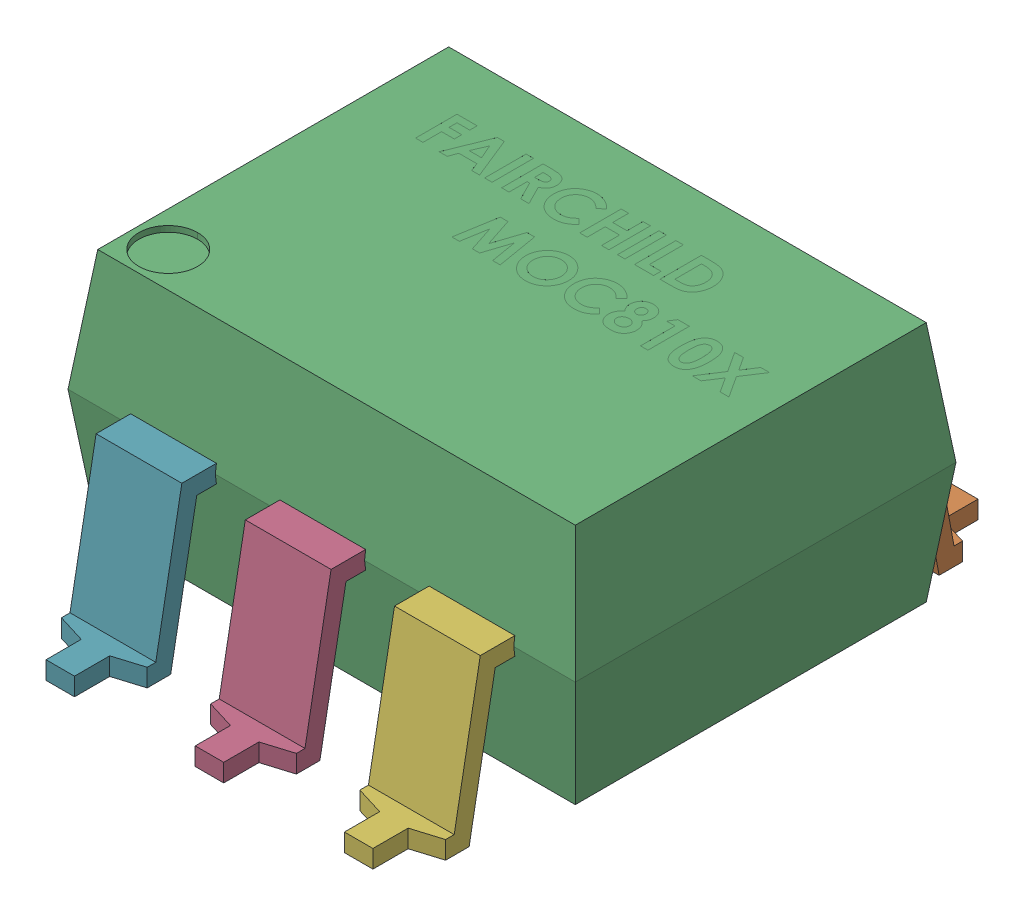
SolidWorks assembly SMD DIP-6_1.step, configuration Default. Lengths in mm.
Overall size (8.63 4.63 10.3).
7 component instances, 2 part files, 0 mates.
Components (placement in the parent):
- MOC810X_SOIC6_PIN_1.step-16: MOC810X_SOIC6_PIN_1.step [Default] at (2.5236 0.1223 -5.1276) x (-1 0 0) z (0 0 -1) size (1.46 2.72 2.11)
- MOC810X_SOIC6_PIN_1.step-17: MOC810X_SOIC6_PIN_1.step [Default] at (5.0636 0.1223 -5.1276) x (-1 0 0) z (0 0 -1) size (1.46 2.72 2.11)
- MOC810X_SOIC6_BODY_1.step-3: MOC810X_SOIC6_BODY_1.step [Default] at (-2.5239 -0.0302 1.3524) size (8.63 4.12 6.48)
- MOC810X_SOIC6_PIN_1.step-18: MOC810X_SOIC6_PIN_1.step [Default] at (1.0636 0.1223 1.3524) size (1.46 2.72 2.11)
- MOC810X_SOIC6_PIN_1.step-19: MOC810X_SOIC6_PIN_1.step [Default] at (-0.0164 0.1223 -5.1276) x (-1 0 0) z (0 0 -1) size (1.46 2.72 2.11)
- MOC810X_SOIC6_PIN_1.step-20: MOC810X_SOIC6_PIN_1.step [Default] at (3.6036 0.1223 1.3524) size (1.46 2.72 2.11)
- MOC810X_SOIC6_PIN_1.step-21: MOC810X_SOIC6_PIN_1.step [Default] at (-1.4764 0.1223 1.3524) size (1.46 2.72 2.11)
